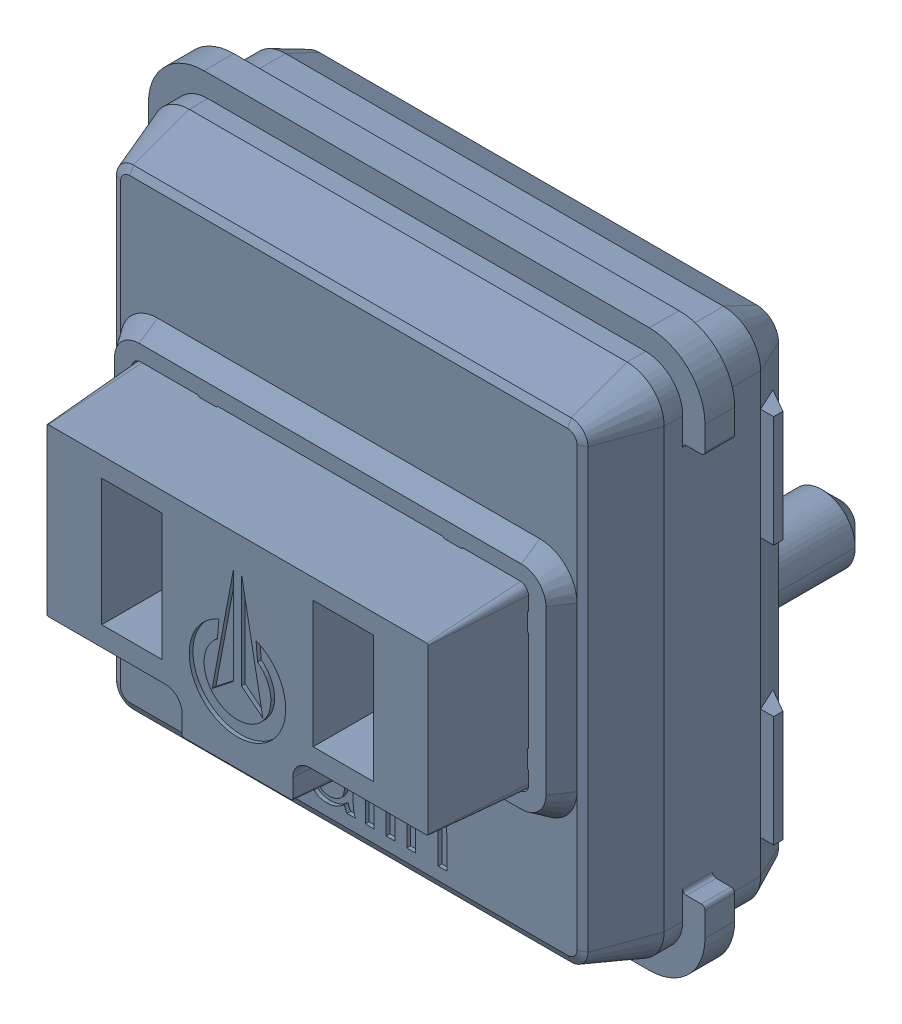
SolidWorks assembly SW4_1.step, configuration Default. Lengths in mm.
Overall size (15 15 11.1).
2 component instances, 2 part files, 0 mates.
Components (placement in the parent):
- Kailh LP Choc Burnt Orange_1.step-3: Kailh LP Choc Burnt Orange_1.step [Default] at (397.1171 226.3933 2.7) x (0 -1 0) z (-1 0 0) size (15 11.1 15)
- WS2812-2020_1.step-3: WS2812-2020_1.step [Default] at (397.2237 231.0345 0.3) x (1 0 0) z (0 -1 0) size (2.2 0.86 2)
